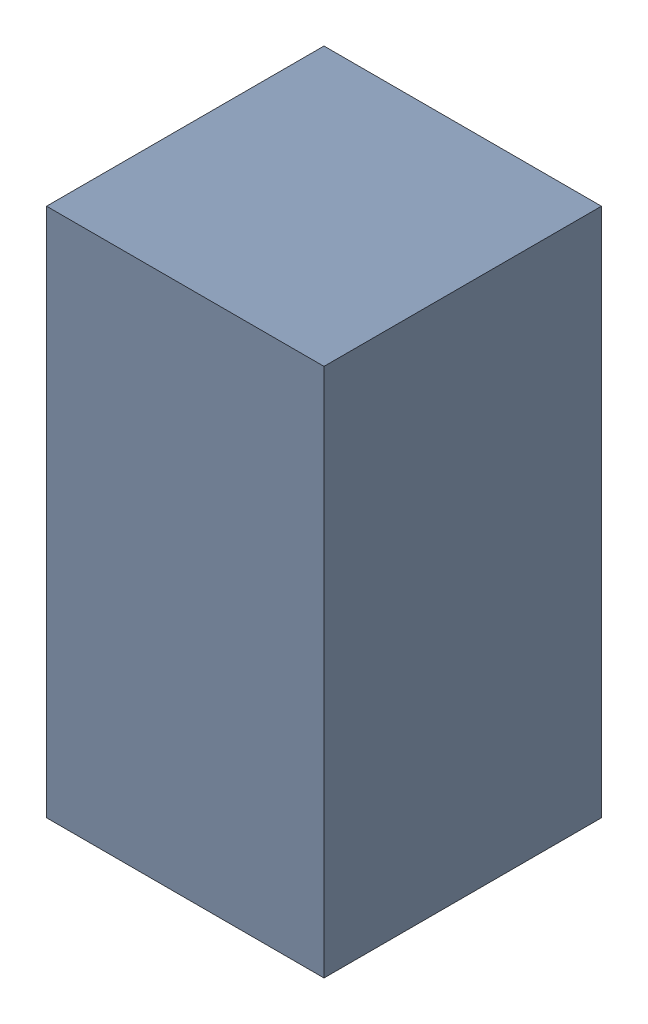
SolidWorks assembly 6327397504, configuration Default. Lengths in mm.
Overall size (0.33 0.63 0.33).
2 component instances, 1 part files, 0 mates.
Components (placement in the parent):
- 6701982208-1:  [Default] at (27.7 14.8 0) (suppressed, hidden)
- Extruded-5-1: Extruded-5 [Default] at origin size (0.33 0.63 0.33)
